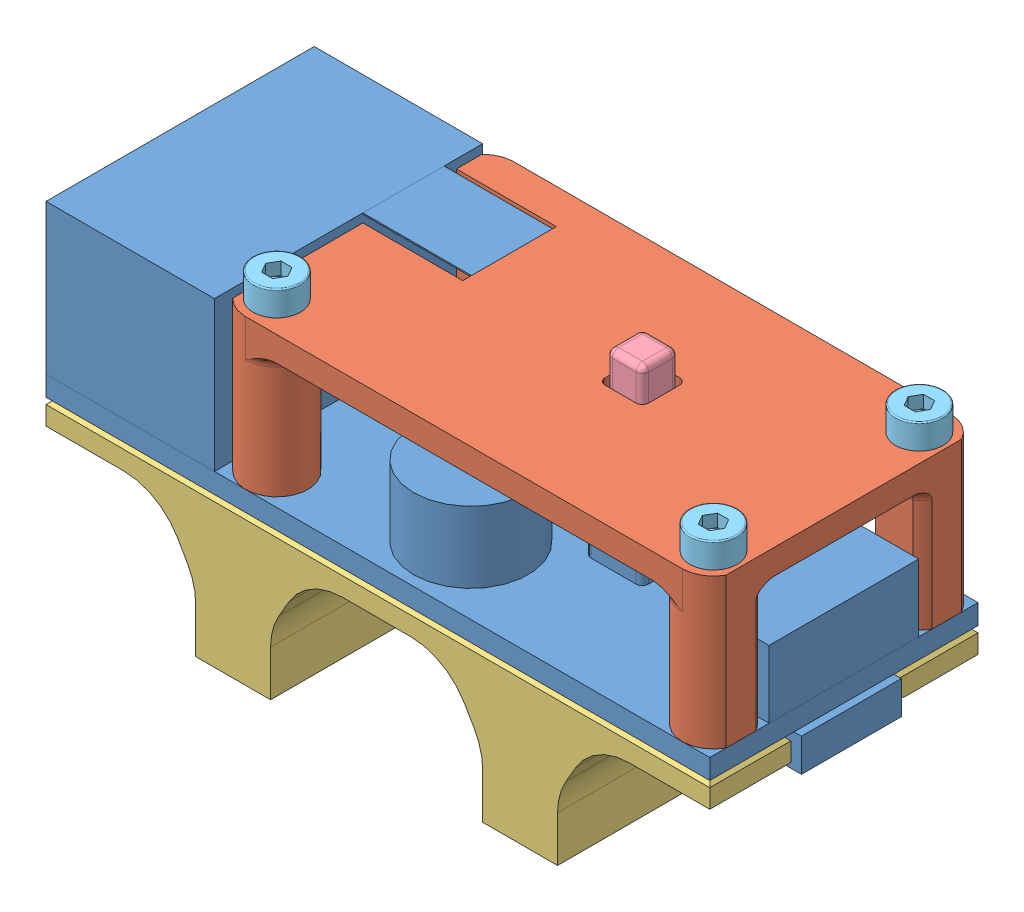
SolidWorks assembly T00005-000-R00, configuration Default. Lengths in mm.
Overall size (53.8 27.95 21.5).
7 component instances, 5 part files, 15 mates.
Components (placement in the parent):
- T00154-E00-R01-1: T00154-E00-R01 [Default] at (15.674 22.2087 43.7303) size (53.8 16.25 21.5)
- T00172-000-R01-1: T00172-000-R01 [Default] at (22.774 33.8087 43.7303) size (39 12 21.5)
- T00171-000-R01-1: T00171-000-R01 [Default] at (15.674 10.2087 43.7303) size (53.2 12 21.5)
- T00173-000-R01-1: T00173-000-R01 [Default] at (25.474 28.1587 43.0803) size (6 10 6)
- socket head cap screw_iso-1: socket head cap screw_iso [ISO 4762 M2 x 16 - 16C] at (40.074 37.8087 51.9803) x (0 -1 0) z (0 0 1) size (18 3.8 3.8)
- socket head cap screw_iso-4: socket head cap screw_iso [ISO 4762 M2 x 16 - 16C] at (5.074 37.8087 51.9803) x (0 -1 0) z (0 0 1) size (18 3.8 3.8)
- socket head cap screw_iso-5: socket head cap screw_iso [ISO 4762 M2 x 16 - 16C] at (40.074 37.8087 35.4803) x (0 -1 0) z (0 0 1) size (18 3.8 3.8)
Mates (geometry in assembly coordinates):
- Concentric1: concentric: cylinder of T00154-E00-R01-1 through (40.074 23.8087 51.9803) axis (0 -1 0) radius 1.1; cylinder of T00172-000-R01-1 through (40.074 33.8087 51.9803) axis (0 1 0) radius 1.25
- Coincident1: coincident: plane of T00154-E00-R01-1 through (15.674 35.8087 43.7303) normal (0 1 0); plane of T00172-000-R01-1 through (22.774 35.8087 43.7303) normal (0 1 0)
- Coincident2: coincident: plane of T00154-E00-R01-1 through (15.674 22.2087 43.7303) normal (0 -1 0); plane of T00171-000-R01-1 through (15.674 22.2087 43.7303) normal (0 1 0)
- Concentric3: concentric: cylinder of T00154-E00-R01-1 through (40.074 23.8087 51.9803) axis (0 -1 0) radius 1.1; cylinder of T00171-000-R01-1 through (40.074 17.2087 51.9803) axis (0 1 0) radius 0.9
- Concentric4: concentric: cylinder of T00154-E00-R01-1 through (5.074 23.8087 35.4803) axis (0 -1 0) radius 1.1; cylinder of T00171-000-R01-1 through (5.074 17.2087 35.4803) axis (0 1 0) radius 0.9
- Width1: width: plane of T00172-000-R01-1 through (22.774 29.8087 43.7303) normal (0 -1 0); plane of T00154-E00-R01-1 through (15.674 27.5087 43.7303) normal (0 1 0); plane of T00173-000-R01-1 through (25.474 29.1587 43.0803) normal (0 1 0); plane of T00173-000-R01-1 through (25.474 28.1587 43.0803) normal (0 -1 0)
- Width2: width: plane of T00173-000-R01-1 through (24.024 38.1587 44.5303) normal (-1 0 0); plane of T00173-000-R01-1 through (26.924 38.1587 44.5303) normal (1 0 0); plane of T00172-000-R01-1 through (27.224 35.8087 41.3303) normal (-1 0 0); plane of T00172-000-R01-1 through (23.724 35.8087 41.3303) normal (1 0 0)
- Width3: width: plane of T00173-000-R01-1 through (24.024 38.1587 44.5303) normal (0 0 1); plane of T00173-000-R01-1 through (24.024 38.1587 41.6303) normal (0 0 -1); plane of T00172-000-R01-1 through (23.724 35.8087 41.3303) normal (0 0 1); plane of T00172-000-R01-1 through (23.724 35.8087 44.8303) normal (0 0 -1)
- Coincident3: coincident: plane of T00172-000-R01-1 through (22.774 35.8087 43.7303) normal (0 1 0); plane of socket head cap screw_iso-4 through (6.974 35.8087 51.9803) normal (0 -1 0)
- Coincident4: coincident: plane of T00172-000-R01-1 through (22.774 35.8087 43.7303) normal (0 1 0); plane of socket head cap screw_iso-1 through (41.974 35.8087 51.9803) normal (0 -1 0)
- Coincident5: coincident: plane of T00172-000-R01-1 through (22.774 35.8087 43.7303) normal (0 1 0); plane of socket head cap screw_iso-5 through (41.974 35.8087 35.4803) normal (0 -1 0)
- Concentric5: concentric: cylinder of T00172-000-R01-1 through (5.074 33.8087 51.9803) axis (0 1 0) radius 1.25; cylinder of socket head cap screw_iso-4 through (5.074 69.5587 51.9803) axis (0 1 0) radius 1
- Concentric6: concentric: cylinder of T00172-000-R01-1 through (40.074 33.8087 51.9803) axis (0 1 0) radius 1.25; cylinder of socket head cap screw_iso-1 through (40.074 69.5587 51.9803) axis (0 1 0) radius 1
- Concentric7: concentric: cylinder of T00172-000-R01-1 through (40.074 33.8087 35.4803) axis (0 1 0) radius 1.25; cylinder of socket head cap screw_iso-5 through (40.074 69.5587 35.4803) axis (0 1 0) radius 1
- Concentric8: concentric: cylinder of T00154-E00-R01-1 through (5.074 23.8087 51.9803) axis (0 -1 0) radius 1.1; cylinder of T00172-000-R01-1 through (5.074 33.8087 51.9803) axis (0 1 0) radius 1.25
